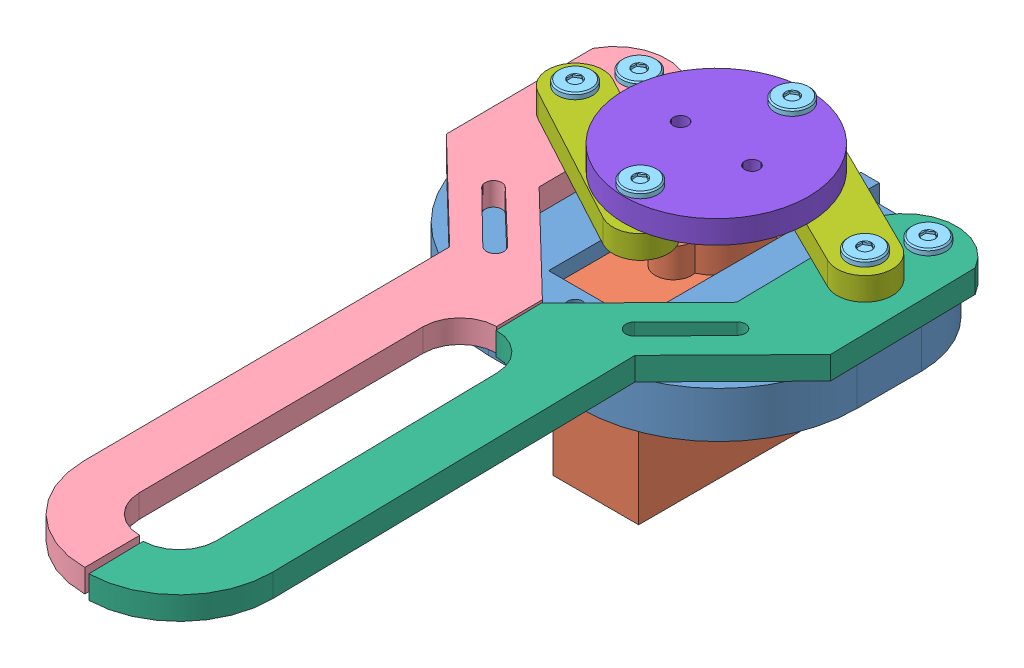
SolidWorks assembly The Claw FINISHED, configuration Default. Lengths in mm.
Overall size (54.32 35.16 104.32).
14 component instances, 8 part files, 25 mates.
Components (placement in the parent):
- gripper base 3D-1: gripper base 3D [Default] at (-6.456 22.2817 53.9657) size (50.8 6.35 41.19)
- Tower Pro Servo Motor SG90-2: Tower Pro Servo Motor SG90 [Default] at (24.775 3.8817 29.2818) x (0 0 1) z (-1 0 0) size (31.9 29.9 11.8)
- servo accessory-1: servo accessory [Default] at (18.875 33.8837 35.1818) x (0.999515 0 0.031157) z (-0.031157 0 0.999515) size (22.86 3.94 5.08)
- gripper left side 3D-1: gripper left side 3D [Default] at (5.936 28.6317 62.6135) x (0.999978 0 -0.006674) z (0.006674 0 0.999978) size (26.3 3.17 100.97)
- 90318A101_ULTRA LOW PROFILE TYPE 316 SS SHOULDER SCREW-1: 90318A101_ULTRA LOW PROFILE TYPE 316 SS SHOULDER SCREW [90318A101] at (-0.9859 32.6005 25.9481) x (1 0 0) z (0 1 0) size (4.76 4.76 7.42)
- gripper right side 3D-1: gripper right side 3D [Default] at (32.4342 28.6317 20.9821) x (0.999841 0 -0.017834) z (0.017834 0 0.999841) size (26.3 3.17 100.97)
- 90318A101_ULTRA LOW PROFILE TYPE 316 SS SHOULDER SCREW-2: 90318A101_ULTRA LOW PROFILE TYPE 316 SS SHOULDER SCREW [90318A101] at (38.8738 32.6005 25.9481) x (1 0 0) z (0 1 0) size (4.76 4.76 7.42)
- open&close lever 3D-1: open&close lever 3D [Default] at (18.5584 31.8067 45.3369) x (0.474349 0 -0.880337) z (0.880337 0 0.474349) size (7.62 3.17 29.75)
- 90318A101_ULTRA LOW PROFILE TYPE 316 SS SHOULDER SCREW-3: 90318A101_ULTRA LOW PROFILE TYPE 316 SS SHOULDER SCREW [90318A101] at (-0.9265 35.7755 34.8379) x (1 0 0) z (0 1 0) size (4.76 4.76 7.42)
- open&close lever 3D-2: open&close lever 3D [Default] at (19.1915 31.8067 25.0268) x (-0.443215 0 0.896415) z (-0.896415 0 -0.443215) size (7.62 3.17 29.75)
- 90318A101_ULTRA LOW PROFILE TYPE 316 SS SHOULDER SCREW-4: 90318A101_ULTRA LOW PROFILE TYPE 316 SS SHOULDER SCREW [90318A101] at (39.0323 35.7755 34.8367) x (1 0 0) z (0 1 0) size (4.76 4.76 7.42)
- open&close revolver 3D-1: open&close revolver 3D [Default] at (18.875 34.9817 35.1818) x (0.999515 0 0.031157) z (-0.031157 0 0.999515) size (25.4 3.17 25.4)
- 90318A101_ULTRA LOW PROFILE TYPE 316 SS SHOULDER SCREW-5: 90318A101_ULTRA LOW PROFILE TYPE 316 SS SHOULDER SCREW [90318A101] at (19.1915 38.9505 25.0268) x (1 0 0) z (0 1 0) size (4.76 4.76 7.42)
- 90318A101_ULTRA LOW PROFILE TYPE 316 SS SHOULDER SCREW-6: 90318A101_ULTRA LOW PROFILE TYPE 316 SS SHOULDER SCREW [90318A101] at (18.5584 38.9505 45.3369) x (0.998759 0 -0.049801) z (0 1 0) size (4.76 4.76 7.42)
Mates (geometry in assembly coordinates):
- Coincident3: coincident anti-aligned: line of gripper base 3D-1 through (24.913 22.2817 29.2818) axis (-1 0 0); line of Tower Pro Servo Motor SG90-2 through (12.975 22.2817 29.2818) axis (1 0 0)
- Coincident6: coincident: plane of gripper base 3D-1 through (12.975 28.6317 29.2818) normal (1 0 0); line of Tower Pro Servo Motor SG90-2 through (12.975 26.5817 51.7818) axis (0 0 -1)
- Concentric5: concentric aligned: cylinder of Tower Pro Servo Motor SG90-2 through (18.875 33.7817 35.1818) axis (0 -1 0) radius 2.3; cylinder of servo accessory-1 through (18.875 33.8837 35.1818) axis (0 -1 0) radius 2.286
- Coincident8: coincident anti-aligned: plane of gripper base 3D-1 through (31.1169 22.2817 32.3757) normal (0 -1 0); plane of Tower Pro Servo Motor SG90-2 through (12.975 22.2817 56.4818) normal (0 1 0)
- Coincident9: coincident anti-aligned: plane of Tower Pro Servo Motor SG90-2 through (18.875 30.5817 38.1318) normal (0 1 0); circle of servo accessory-1
- Concentric7: concentric aligned: circle of gripper base 3D-1; circle of gripper right side 3D-1
- Coincident13: coincident anti-aligned: plane of gripper base 3D-1 through (31.1169 28.6317 32.3757) normal (0 1 0); plane of gripper right side 3D-1 through (20.4287 28.6317 110.7455) normal (0 -1 0)
- Coincident14: coincident anti-aligned: circle of gripper right side 3D-1; circle of 90318A101_ULTRA LOW PROFILE TYPE 316 SS SHOULDER SCREW-2
- Concentric8: concentric aligned: circle of gripper base 3D-1; circle of gripper left side 3D-1
- Coincident16: coincident anti-aligned: plane of gripper base 3D-1 through (31.1169 28.6317 32.3757) normal (0 1 0); plane of gripper left side 3D-1 through (19.269 28.6317 70.8989) normal (0 -1 0)
- Concentric9: concentric aligned: cylinder of gripper left side 3D-1 through (-0.9859 31.8067 25.9481) axis (0 -1 0) radius 1.1906; cylinder of 90318A101_ULTRA LOW PROFILE TYPE 316 SS SHOULDER SCREW-1 through (-0.9859 25.4567 25.9481) axis (0 -1 0) radius 1.1906
- Coincident17: coincident anti-aligned: plane of gripper left side 3D-1 through (19.269 31.8067 70.8989) normal (0 1 0); plane of 90318A101_ULTRA LOW PROFILE TYPE 316 SS SHOULDER SCREW-1 through (-0.9859 31.8067 28.3293) normal (0 -1 0)
- Concentric10: concentric aligned: circle of gripper left side 3D-1; circle of open&close lever 3D-1
- Coincident18: coincident anti-aligned: plane of gripper left side 3D-1 through (19.269 31.8067 70.8989) normal (0 1 0); plane of open&close lever 3D-1 through (18.5703 31.8067 45.3148) normal (0 -1 0)
- Coincident20: coincident anti-aligned: circle of open&close lever 3D-1; circle of 90318A101_ULTRA LOW PROFILE TYPE 316 SS SHOULDER SCREW-3
- Concentric11: concentric aligned: circle of gripper right side 3D-1; circle of open&close lever 3D-2
- Coincident21: coincident anti-aligned: plane of gripper right side 3D-1 through (20.4287 31.8067 110.7455) normal (0 1 0); plane of open&close lever 3D-2 through (19.1804 31.8067 25.0492) normal (0 -1 0)
- Coincident22: coincident anti-aligned: circle of open&close lever 3D-2; circle of 90318A101_ULTRA LOW PROFILE TYPE 316 SS SHOULDER SCREW-4
- Concentric12: concentric aligned: circle of open&close lever 3D-2; circle of open&close revolver 3D-1
- Coincident23: coincident anti-aligned: plane of open&close lever 3D-2 through (19.1804 34.9817 25.0492) normal (0 1 0); plane of open&close revolver 3D-1 through (18.875 34.9817 35.1818) normal (0 -1 0)
- Coincident24: coincident anti-aligned: circle of open&close revolver 3D-1; circle of 90318A101_ULTRA LOW PROFILE TYPE 316 SS SHOULDER SCREW-5
- Concentric13: concentric aligned: circle of open&close lever 3D-1; circle of open&close revolver 3D-1
- Coincident26: coincident anti-aligned: circle of open&close revolver 3D-1; circle of 90318A101_ULTRA LOW PROFILE TYPE 316 SS SHOULDER SCREW-6
- Concentric14: concentric aligned: circle of servo accessory-1; circle of open&close revolver 3D-1
- Concentric15: concentric aligned: circle of servo accessory-1; circle of open&close revolver 3D-1
